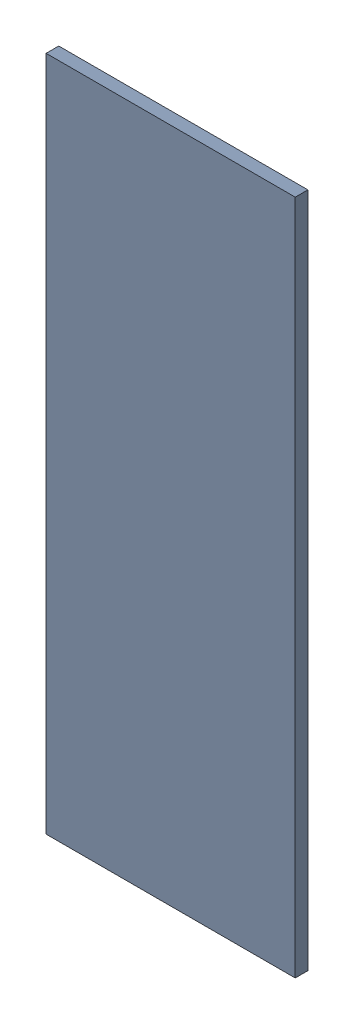
SolidWorks assembly Pad RAK4600-41(18.725mm,31.391mm) on Top Layer, configuration Predeterminado. Lengths in mm.
Overall size (0.7 1.9 0.04).
2 component instances, 1 part files, 0 mates.
Components (placement in the parent):
- Pad RAK4600-41(18.725mm,31.391mm) on Top Layer-1-1: Pad RAK4600-41(18.725mm,31.391mm) on Top Layer-1 [Predeterminado] at (-68.317 -44.187 -0.0457) size (0.7 1.9 0.04)
  - Pad RAK4600-41(18.725mm,31.391mm) on Top Layer-Part-1-1: Pad RAK4600-41(18.725mm,31.391mm) on Top Layer-Part-1 [Predeterminado] at origin size (0.7 1.9 0.04)
